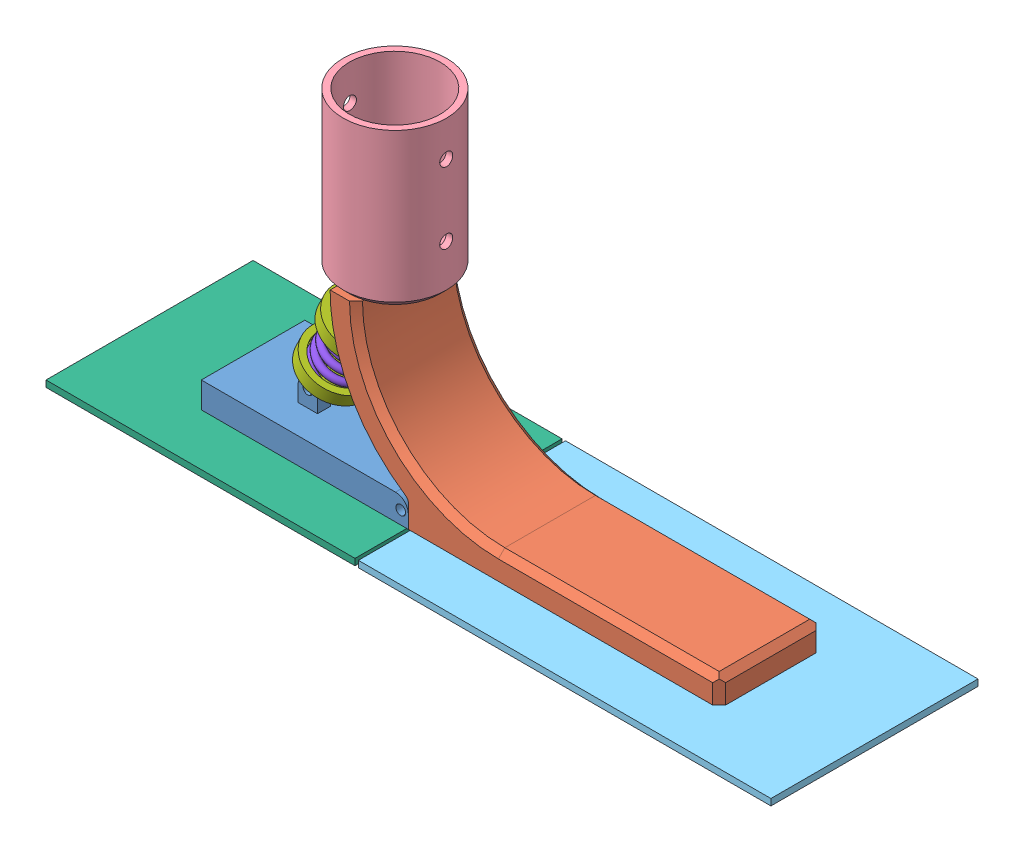
SolidWorks assembly Ankle Subassembly, configuration Default. Lengths in mm.
Overall size (355.68 161.93 101.6).
11 component instances, 8 part files, 18 mates.
Components (placement in the parent):
- Heel Plate-1: Heel Plate [Default] at (-35.1834 69.1132 56.8764) size (101.6 25.4 50.8)
- sach ankle-1: sach ankle [Default] at (110.567 138.9634 56.8764) size (201 82.55 50.8)
- Ankle locater Pin-1: Ankle locater Pin [Default] at (34.367 132.6134 94.9764) size (3.17 12.7 3.17)
- Ankle locater Pin-2: Ankle locater Pin [Default] at (34.367 132.6134 69.5764) x (0.162276 0 0.986745) z (-0.986745 0 0.162276) size (3.17 12.7 3.17)
- Ankle Top Piece-1: Ankle Top Piece [Default] at (34.367 138.9634 82.2764) x (0 0 1) z (-1 0 0) size (50.8 76.2 50.8)
- Front Skidplate-1: Front Skidplate [Default] at (67.2918 56.4134 133.0764) x (1 0 0) z (0 -1 0) size (202.41 101.6 3.17)
- Back Skidplate-1: Back Skidplate [Default] at (-85.9834 56.4132 133.0764) size (151.61 3.17 101.6)
- Spring guide assembly-2: Spring guide assembly [Default] at (38.8834 109.0009 108.3942) x (0.900984 -0.433852 0) z (0 0 1) size (31.75 56.77 31.75)
  - SPRING GUIDE-1: SPRING GUIDE [Default] at (-18.26 5.2904 -26.1179) size (31.75 18.86 31.75)
  - SPRING GUIDE-2: SPRING GUIDE [Default] at (-18.26 -51.4786 -26.1179) x (-1 0 0) z (0 0 1) size (31.75 18.86 31.75)
  - Heel Spring-1: Heel Spring [9657K513] at (-18.0668 -48.4941 -26.2147) x (1 0 0) z (0 -1 0) size (26.33 25.44 26.85)
Mates (geometry in assembly coordinates):
- Coincident2: coincident aligned: plane of Heel Plate-1 through (60.092 62.7886 56.8764) normal (0 0 -1); plane of sach ankle-1 through (110.567 138.9634 56.8764) normal (0 0 -1)
- LimitDistance1: limit distance = 0.0762 mm anti-aligned: plane of sach ankle-1 through (66.4928 58.9786 107.6764) normal (-1 0 0); plane of Heel Plate-1 through (66.4166 62.7886 107.6764) normal (1 0 0)
- Coincident3: coincident anti-aligned: line of sach ankle-1 through (34.367 132.6134 69.5764) axis (0 1 0); line of Ankle locater Pin-2 through (34.367 145.3134 69.5764) axis (0 -1 0)
- Coincident4: coincident anti-aligned: plane of sach ankle-1 through (34.367 132.6134 69.5764) normal (0 1 0); plane of Ankle locater Pin-2 through (34.367 132.6134 69.5764) normal (0 -1 0)
- Coincident6: coincident anti-aligned: line of sach ankle-1 through (34.367 132.6134 94.9764) axis (0 1 0); line of Ankle locater Pin-1 through (34.367 145.3134 94.9764) axis (0 -1 0)
- Coincident7: coincident aligned: plane of sach ankle-1 through (34.367 132.6134 94.9764) normal (0 1 0); circle of Ankle locater Pin-1
- Coincident8: coincident aligned: line of sach ankle-1 through (34.367 132.6134 94.9764) axis (0 1 0); line of Ankle Top Piece-1 through (34.367 138.9634 94.9764) axis (0 1 0)
- Coincident9: coincident anti-aligned: line of Ankle locater Pin-2 through (34.367 145.3134 69.5764) axis (0 -1 0); line of Ankle Top Piece-1 through (34.367 138.9634 69.5764) axis (0 1 0)
- Coincident10: coincident anti-aligned: plane of sach ankle-1 through (40.717 138.9634 107.6764) normal (0 1 0); plane of Ankle Top Piece-1 through (34.367 138.9634 82.2764) normal (0 -1 0)
- Coincident12: coincident anti-aligned: plane of sach ankle-1 through (218.898 56.4134 107.6764) normal (0 -1 0); plane of Front Skidplate-1 through (67.2918 56.4134 31.4764) normal (0 1 0)
- Distance2: distance = 50.8 mm aligned: plane of Front Skidplate-1 through (269.698 56.4134 31.4764) normal (1 0 0); plane of sach ankle-1 through (218.898 69.1134 107.6764) normal (1 0 0)
- Distance4: distance = 25.4 mm aligned: plane of Front Skidplate-1 through (67.2918 56.4134 31.4764) normal (0 0 -1); plane of sach ankle-1 through (110.567 138.9634 56.8764) normal (0 0 -1)
- Coincident14: coincident anti-aligned: line of Heel Plate-1 through (62.6828 62.7886 75.9645) axis (0 0 1); line of sach ankle-1 through (62.6828 62.7886 75.9264) axis (0 0 -1)
- Distance6: distance = 25.4 mm aligned: plane of Heel Plate-1 through (60.092 62.7886 56.8764) normal (0 0 -1); plane of Back Skidplate-1 through (-85.9834 56.4132 31.4764) normal (0 0 -1)
- Coincident16: coincident anti-aligned: plane of Heel Plate-1 through (-35.1834 56.4132 107.6764) normal (0 -1 0); plane of Back Skidplate-1 through (-85.9834 56.4132 31.4764) normal (0 1 0)
- Distance8: distance = 50.8 mm aligned: plane of Heel Plate-1 through (-35.1834 69.1132 107.6764) normal (-1 0 0); plane of Back Skidplate-1 through (-85.9834 56.4132 31.4764) normal (-1 0 0)
- Coincident17: coincident anti-aligned: line of sach ankle-1 through (22.6605 117.3986 77.1329) axis (0 0 -1); line of Spring guide assembly-2/SPRING GUIDE-1 through (22.6605 117.3986 77.5267) axis (0 0 1)
- Distance9: distance = 4.8895 mm: plane of assembly; axis of Spring guide assembly-2/SPRING GUIDE-1 through (22.4038 116.8657 82.2764) axis (0.433852 0.900984 0); plane of sach ankle-1 through (110.6307 138.6099 77.3869) normal (0 0 1)
